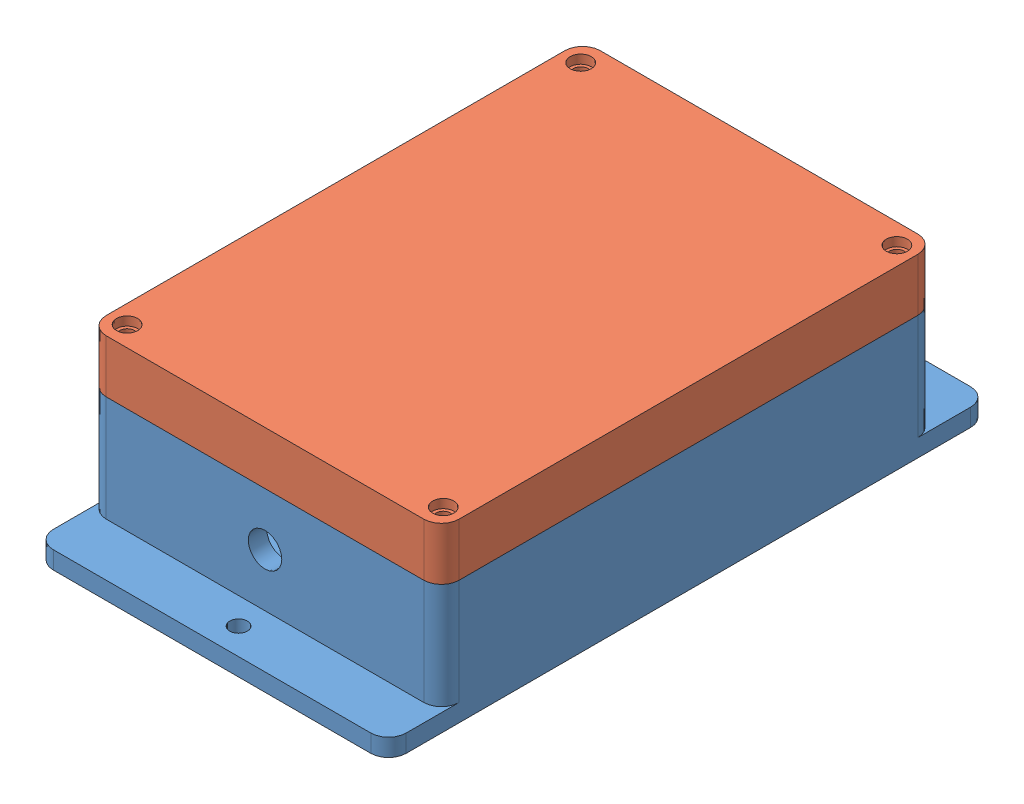
SolidWorks assembly Assem1, configuration Default. Lengths in mm.
Overall size (100 50 170).
2 component instances, 2 part files, 5 mates.
Components (placement in the parent):
- Base1-1: Base1 [Default] at (69.3133 102.1145 109.5236) size (100 37 170)
- Top V2-1: Top V2 [Default] at (69.3133 144.6145 109.5236) x (-1 0 0) z (0 0 1) size (100 15 140)
Mates (geometry in assembly coordinates):
- Concentric5: concentric aligned: cylinder of Base1-1 through (24.3133 132.1145 174.5236) axis (0 -1 0) radius 5; cylinder of Top V2-1 through (24.3133 147.1145 174.5236) axis (0 -1 0) radius 5
- Concentric6: concentric aligned: cylinder of Base1-1 through (114.3133 97.1145 174.5236) axis (0 -1 0) radius 5; cylinder of Top V2-1 through (114.3133 147.1145 174.5236) axis (0 -1 0) radius 5
- Concentric7: concentric aligned: cylinder of Base1-1 through (114.3133 132.1145 44.5236) axis (0 -1 0) radius 5; cylinder of Top V2-1 through (114.3133 147.1145 44.5236) axis (0 -1 0) radius 5
- Concentric8: concentric aligned: cylinder of Base1-1 through (24.3133 97.1145 44.5236) axis (0 -1 0) radius 5; cylinder of Top V2-1 through (24.3133 147.1145 44.5236) axis (0 -1 0) radius 5
- Coincident3: coincident anti-aligned: circle of Base1-1; circle of Top V2-1
